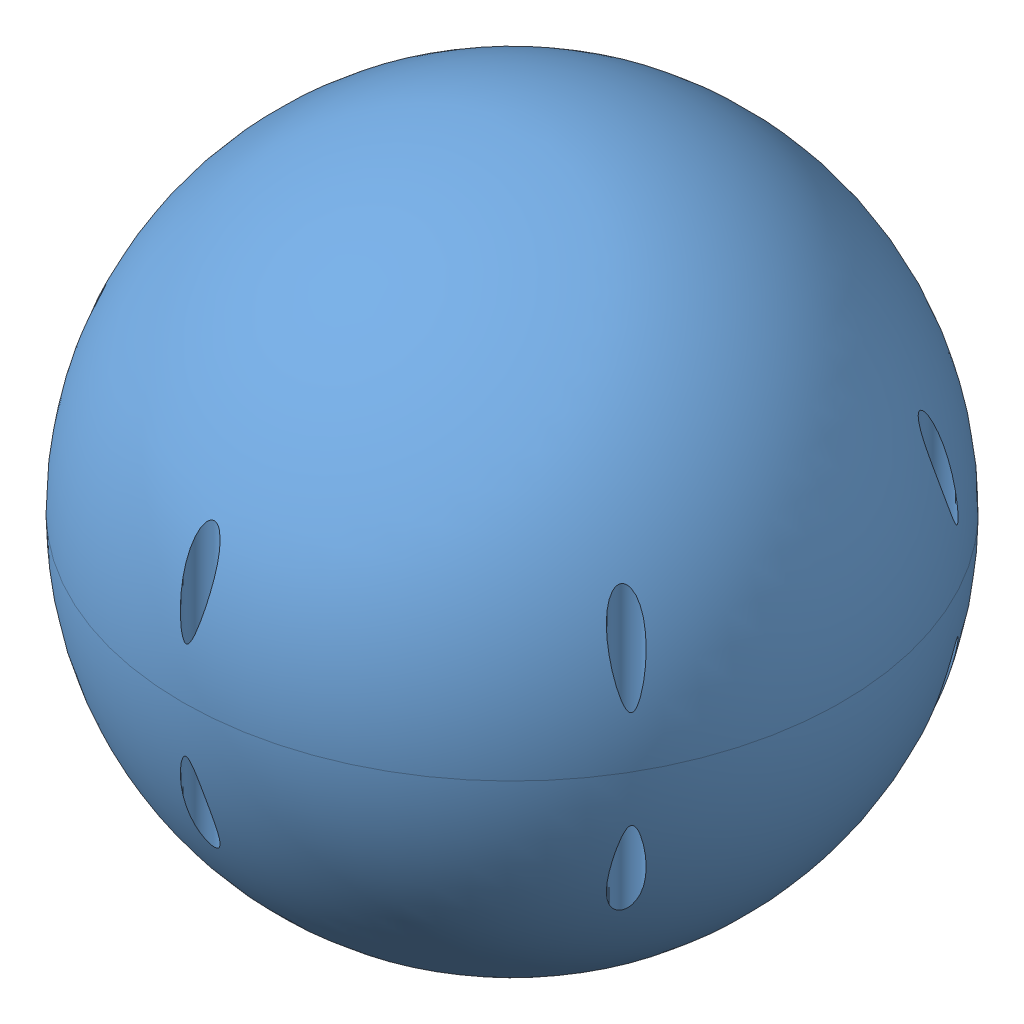
SolidWorks assembly Lower Ball Assembly, configuration Default. Lengths in mm.
Overall size (184.15 184.15 184.46).
14 component instances, 3 part files, 27 mates.
Components (placement in the parent):
- BB-8 Body Shell-1: BB-8 Body Shell [Default] at (88.6528 76.0248 193.4788) size (184.15 92.08 184.15)
- BB-8 Body Shell-2: BB-8 Body Shell [Default] at (88.6528 260.1748 193.4788) x (-1 0 0) z (0 0 1) size (184.15 92.08 184.15)
- 95868A110_NYLON SOCKET HEAD CAP SCREW-1: 95868A110_NYLON SOCKET HEAD CAP SCREW [95868A110] at (164.1026 158.5748 149.9178) x (1 0 0) z (0 -1 0) size (4.65 4.65 16.24)
- 95868A110_NYLON SOCKET HEAD CAP SCREW-2: 95868A110_NYLON SOCKET HEAD CAP SCREW [95868A110] at (13.2029 158.5748 237.0398) x (1 0 0) z (0 -1 0) size (4.65 4.65 16.24)
- 95868A110_NYLON SOCKET HEAD CAP SCREW-3: 95868A110_NYLON SOCKET HEAD CAP SCREW [95868A110] at (164.1026 158.5748 237.0398) x (1 0 0) z (0 -1 0) size (4.65 4.65 16.24)
- 95868A110_NYLON SOCKET HEAD CAP SCREW-4: 95868A110_NYLON SOCKET HEAD CAP SCREW [95868A110] at (13.2029 158.5748 149.9178) x (1 0 0) z (0 -1 0) size (4.65 4.65 16.24)
- 95868A110_NYLON SOCKET HEAD CAP SCREW-5: 95868A110_NYLON SOCKET HEAD CAP SCREW [95868A110] at (88.6528 158.5748 106.3568) x (1 0 0) z (0 -1 0) size (4.65 4.65 16.24)
- 95868A110_NYLON SOCKET HEAD CAP SCREW-6: 95868A110_NYLON SOCKET HEAD CAP SCREW [95868A110] at (88.6528 158.5748 280.6008) x (1 0 0) z (0 -1 0) size (4.65 4.65 16.24)
- 94812A112_NYLON 6-6 HEX NUT-1: 94812A112_NYLON 6-6 HEX NUT [94812A112] at (88.6528 163.7341 280.6008) x (-0.837169 0 -0.546944) z (-0.546944 0 0.837169) size (6.75 3.01 7.79)
- 94812A112_NYLON 6-6 HEX NUT-2: 94812A112_NYLON 6-6 HEX NUT [94812A112] at (13.2029 163.7341 149.9178) x (-0.837169 0 -0.546944) z (-0.546944 0 0.837169) size (6.75 3.01 7.79)
- 94812A112_NYLON 6-6 HEX NUT-3: 94812A112_NYLON 6-6 HEX NUT [94812A112] at (164.1026 163.7341 149.9178) x (-0.837169 0 -0.546944) z (-0.546944 0 0.837169) size (6.75 3.01 7.79)
- 94812A112_NYLON 6-6 HEX NUT-4: 94812A112_NYLON 6-6 HEX NUT [94812A112] at (164.1026 163.7341 237.0398) x (-0.837169 0 -0.546944) z (-0.546944 0 0.837169) size (6.75 3.01 7.79)
- 94812A112_NYLON 6-6 HEX NUT-5: 94812A112_NYLON 6-6 HEX NUT [94812A112] at (88.6528 163.7341 106.3568) x (-0.837169 0 -0.546944) z (-0.546944 0 0.837169) size (6.75 3.01 7.79)
- 94812A112_NYLON 6-6 HEX NUT-6: 94812A112_NYLON 6-6 HEX NUT [94812A112] at (13.2029 163.7341 237.0398) x (-0.837169 0 -0.546944) z (-0.546944 0 0.837169) size (6.75 3.01 7.79)
Mates (geometry in assembly coordinates):
- Coincident1: coincident anti-aligned: plane of BB-8 Body Shell-1 through (88.6528 168.0998 193.4788) normal (0 1 0); plane of BB-8 Body Shell-2 through (88.6528 168.0998 193.4788) normal (0 -1 0)
- Concentric1: concentric anti-aligned: cylinder of BB-8 Body Shell-1 through (164.1026 117.2998 237.0398) axis (0 1 0) radius 3.937; cylinder of BB-8 Body Shell-2 through (164.1026 218.8998 237.0398) axis (0 -1 0) radius 3.937
- Concentric2: concentric anti-aligned: cylinder of BB-8 Body Shell-1 through (88.6528 117.2998 280.6008) axis (0 1 0) radius 3.937; cylinder of BB-8 Body Shell-2 through (88.6528 218.8998 280.6008) axis (0 -1 0) radius 3.937
- Coincident2: coincident anti-aligned: plane of BB-8 Body Shell-2 through (13.2029 171.2748 237.0398) normal (0 1 0); plane of 95868A110_NYLON SOCKET HEAD CAP SCREW-2 through (13.2029 171.2748 237.0398) normal (0 -1 0)
- Concentric3: concentric aligned: circle of BB-8 Body Shell-2; circle of 95868A110_NYLON SOCKET HEAD CAP SCREW-2
- Coincident3: coincident anti-aligned: plane of BB-8 Body Shell-2 through (88.6528 171.2748 280.6008) normal (0 1 0); plane of 95868A110_NYLON SOCKET HEAD CAP SCREW-6 through (88.6528 171.2748 280.6008) normal (0 -1 0)
- Concentric4: concentric aligned: circle of BB-8 Body Shell-2; circle of 95868A110_NYLON SOCKET HEAD CAP SCREW-6
- Coincident4: coincident anti-aligned: plane of BB-8 Body Shell-2 through (164.1026 171.2748 237.0398) normal (0 1 0); plane of 95868A110_NYLON SOCKET HEAD CAP SCREW-3 through (164.1026 171.2748 237.0398) normal (0 -1 0)
- Concentric5: concentric aligned: circle of BB-8 Body Shell-2; circle of 95868A110_NYLON SOCKET HEAD CAP SCREW-3
- Coincident5: coincident anti-aligned: plane of BB-8 Body Shell-2 through (164.1026 171.2748 149.9178) normal (0 1 0); plane of 95868A110_NYLON SOCKET HEAD CAP SCREW-1 through (164.1026 171.2748 149.9178) normal (0 -1 0)
- Concentric6: concentric aligned: cylinder of BB-8 Body Shell-2 through (164.1026 171.2748 149.9178) axis (0 -1 0) radius 1.4224; circle of 95868A110_NYLON SOCKET HEAD CAP SCREW-1
- Coincident6: coincident anti-aligned: plane of BB-8 Body Shell-2 through (88.6528 171.2748 106.3568) normal (0 1 0); plane of 95868A110_NYLON SOCKET HEAD CAP SCREW-5 through (88.6528 171.2748 106.3568) normal (0 -1 0)
- Concentric7: concentric anti-aligned: circle of BB-8 Body Shell-1; circle of 95868A110_NYLON SOCKET HEAD CAP SCREW-5
- Coincident7: coincident anti-aligned: plane of BB-8 Body Shell-2 through (13.2029 171.2748 149.9178) normal (0 1 0); plane of 95868A110_NYLON SOCKET HEAD CAP SCREW-4 through (13.2029 171.2748 149.9178) normal (0 -1 0)
- Concentric8: concentric aligned: circle of BB-8 Body Shell-2; circle of 95868A110_NYLON SOCKET HEAD CAP SCREW-4
- Coincident9: coincident anti-aligned: plane of BB-8 Body Shell-1 through (13.2029 164.9248 237.0398) normal (0 -1 0); plane of 94812A112_NYLON 6-6 HEX NUT-6 through (17.0923 164.9248 237.2543) normal (0 1 0)
- Concentric9: concentric aligned: circle of 95868A110_NYLON SOCKET HEAD CAP SCREW-2; circle of 94812A112_NYLON 6-6 HEX NUT-6
- Coincident10: coincident anti-aligned: plane of BB-8 Body Shell-1 through (13.2029 164.9248 149.9178) normal (0 -1 0); plane of 94812A112_NYLON 6-6 HEX NUT-2 through (17.0923 164.9248 150.1323) normal (0 1 0)
- Concentric10: concentric aligned: circle of 95868A110_NYLON SOCKET HEAD CAP SCREW-4; circle of 94812A112_NYLON 6-6 HEX NUT-2
- Coincident11: coincident anti-aligned: plane of BB-8 Body Shell-1 through (88.6528 164.9248 106.3568) normal (0 -1 0); plane of 94812A112_NYLON 6-6 HEX NUT-5 through (92.5421 164.9248 106.5713) normal (0 1 0)
- Concentric11: concentric aligned: circle of 95868A110_NYLON SOCKET HEAD CAP SCREW-5; circle of 94812A112_NYLON 6-6 HEX NUT-5
- Coincident12: coincident anti-aligned: plane of BB-8 Body Shell-1 through (164.1026 164.9248 149.9178) normal (0 -1 0); plane of 94812A112_NYLON 6-6 HEX NUT-3 through (167.992 164.9248 150.1323) normal (0 1 0)
- Concentric12: concentric aligned: circle of 95868A110_NYLON SOCKET HEAD CAP SCREW-1; circle of 94812A112_NYLON 6-6 HEX NUT-3
- Coincident13: coincident anti-aligned: plane of BB-8 Body Shell-1 through (164.1026 164.9248 237.0398) normal (0 -1 0); plane of 94812A112_NYLON 6-6 HEX NUT-1 through (92.5421 164.9248 280.8153) normal (0 1 0)
- Concentric13: concentric aligned: circle of 95868A110_NYLON SOCKET HEAD CAP SCREW-6; circle of 94812A112_NYLON 6-6 HEX NUT-1
- Coincident16: coincident anti-aligned: plane of BB-8 Body Shell-1 through (164.1026 164.9248 237.0398) normal (0 -1 0); plane of 94812A112_NYLON 6-6 HEX NUT-4 through (167.992 164.9248 237.2543) normal (0 1 0)
- Concentric14: concentric aligned: circle of 95868A110_NYLON SOCKET HEAD CAP SCREW-3; circle of 94812A112_NYLON 6-6 HEX NUT-4
